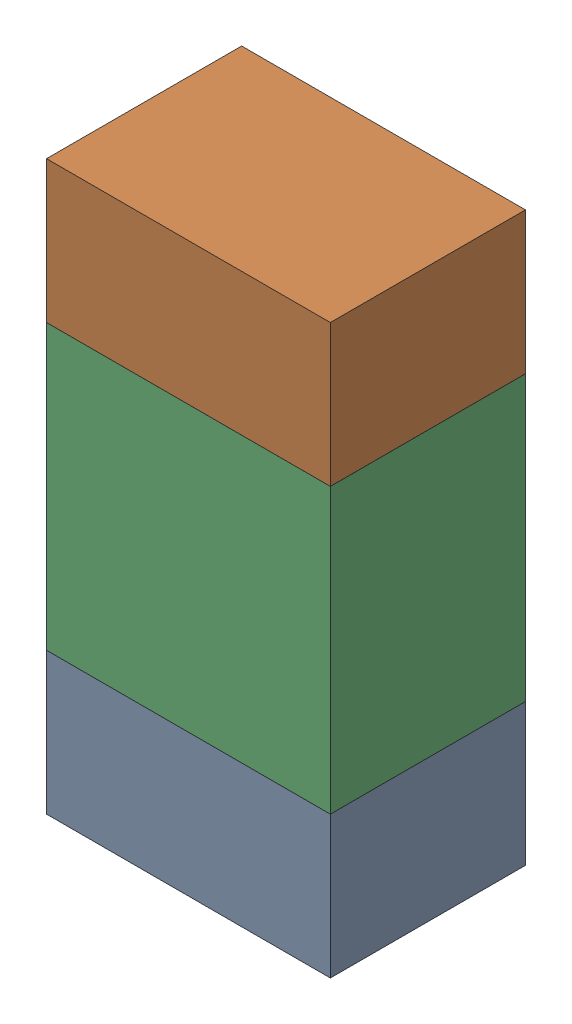
SolidWorks assembly R27, configuration ﾃﾞﾌｫﾙﾄ. Lengths in mm.
Overall size (0.8 1.6 0.55).
6 component instances, 2 part files, 0 mates.
Components (placement in the parent):
- 689261784-1: 689261784 [ﾃﾞﾌｫﾙﾄ] at (26.4999 69.1501 0) size (0.8 0.4 0.55)
  - Extruded_34-1: Extruded_34 [ﾃﾞﾌｫﾙﾄ] at origin size (0.8 0.4 0.55)
- 689261784-2: 689261784 [ﾃﾞﾌｫﾙﾄ] at (26.4999 70.3501 0) size (0.8 0.4 0.55)
  - Extruded_34-1: Extruded_34 [ﾃﾞﾌｫﾙﾄ] at origin size (0.8 0.4 0.55)
- 689261648-1: 689261648 [ﾃﾞﾌｫﾙﾄ] at (26.4999 69.75 0) size (0.8 0.8 0.55)
  - Extruded_33-1: Extruded_33 [ﾃﾞﾌｫﾙﾄ] at origin size (0.8 0.8 0.55)
